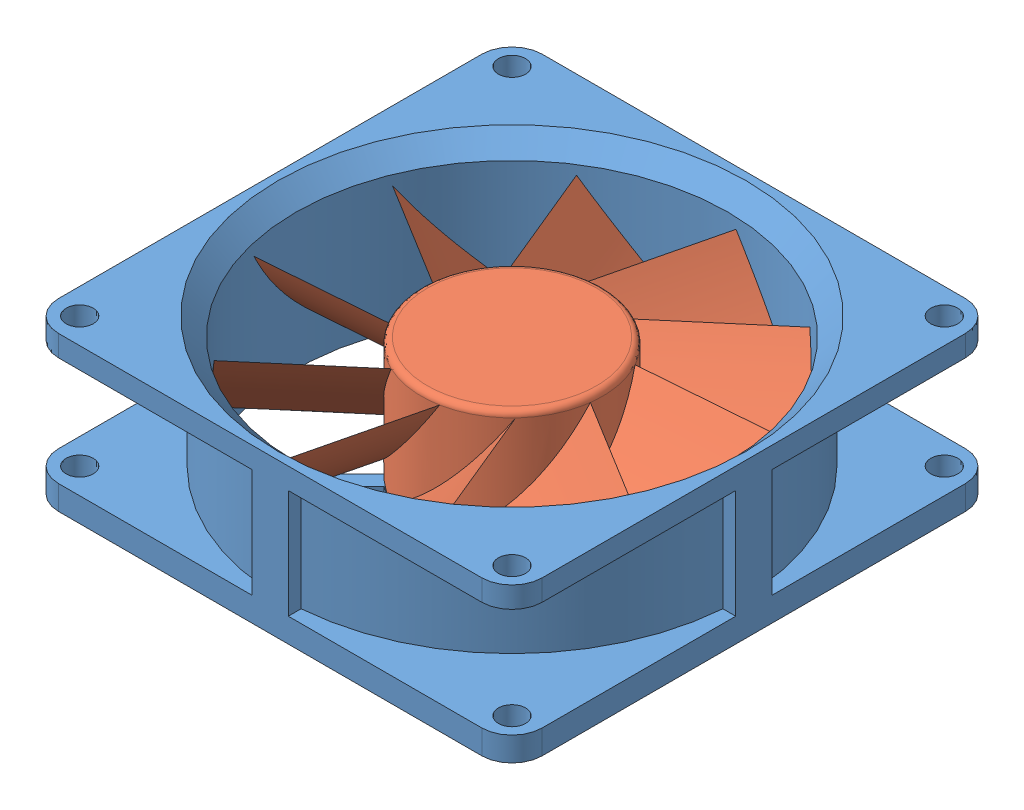
SolidWorks assembly fan, configuration Default. Lengths in mm.
Overall size (80 25.5 80).
2 component instances, 2 part files, 2 mates.
Components (placement in the parent):
- stator-1: stator [Default] at origin size (80 25.5 80)
- rotor-1: rotor [Default] at (0 2.5 0) x (0.997026 0 -0.077067) z (0.077067 0 0.997026) size (70 23.35 70)
Mates (geometry in assembly coordinates):
- Concentric1: concentric: cylinder of stator-1 through (0 19.5 0) axis (0 -1 0) radius 3; cylinder of rotor-1 through (0 20 0) axis (0 -1 0) radius 3
- Distance1: distance = 0.5 mm: plane of stator-1 through (0 2 0) normal (0 1 0); plane of rotor-1 through (0 2.5 0) normal (0 -1 0)
